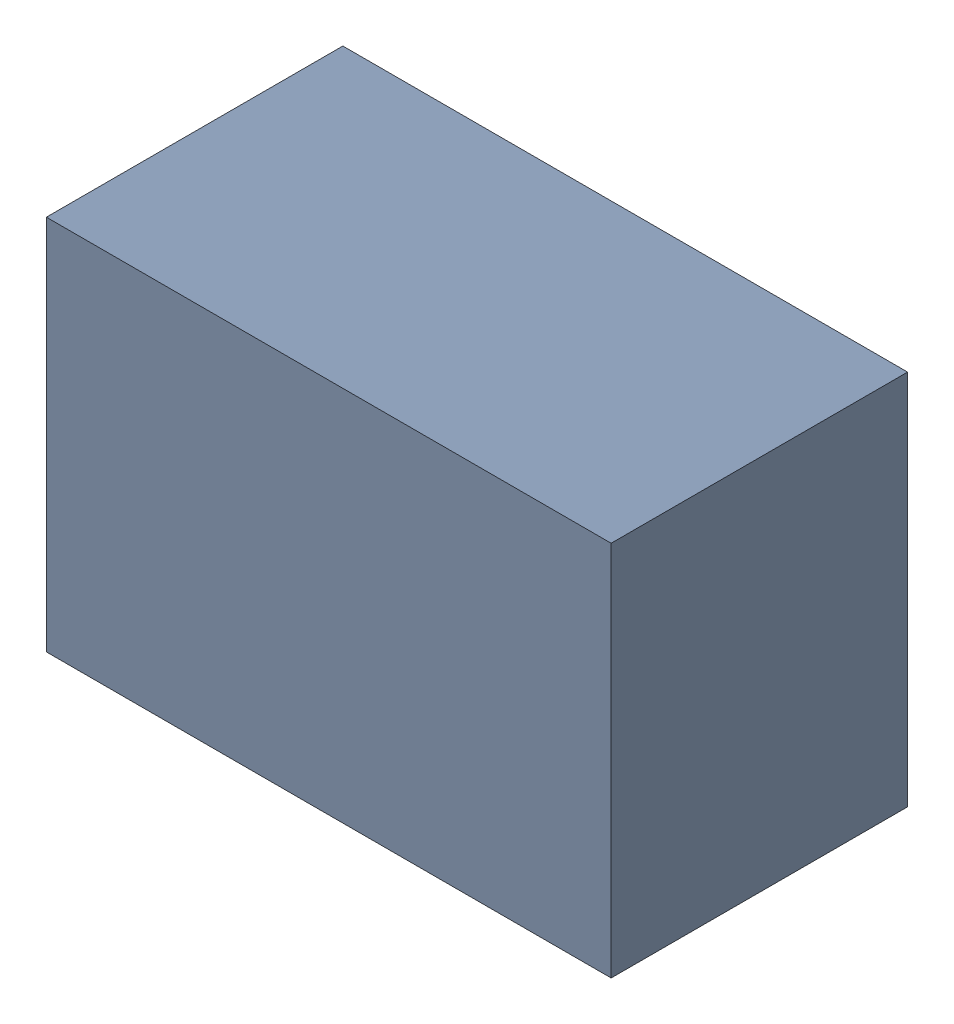
SolidWorks assembly USB45_L2, configuration Default. Lengths in mm.
Overall size (2.29 1.52 1.2).
2 component instances, 1 part files, 0 mates.
Components (placement in the parent):
- 402659088-1: 402659088 [Default] at (156.718 44.704 -2.3024) size (2.29 1.52 1.2)
  - Extruded_28-1: Extruded_28 [Default] at origin size (2.29 1.52 1.2)
